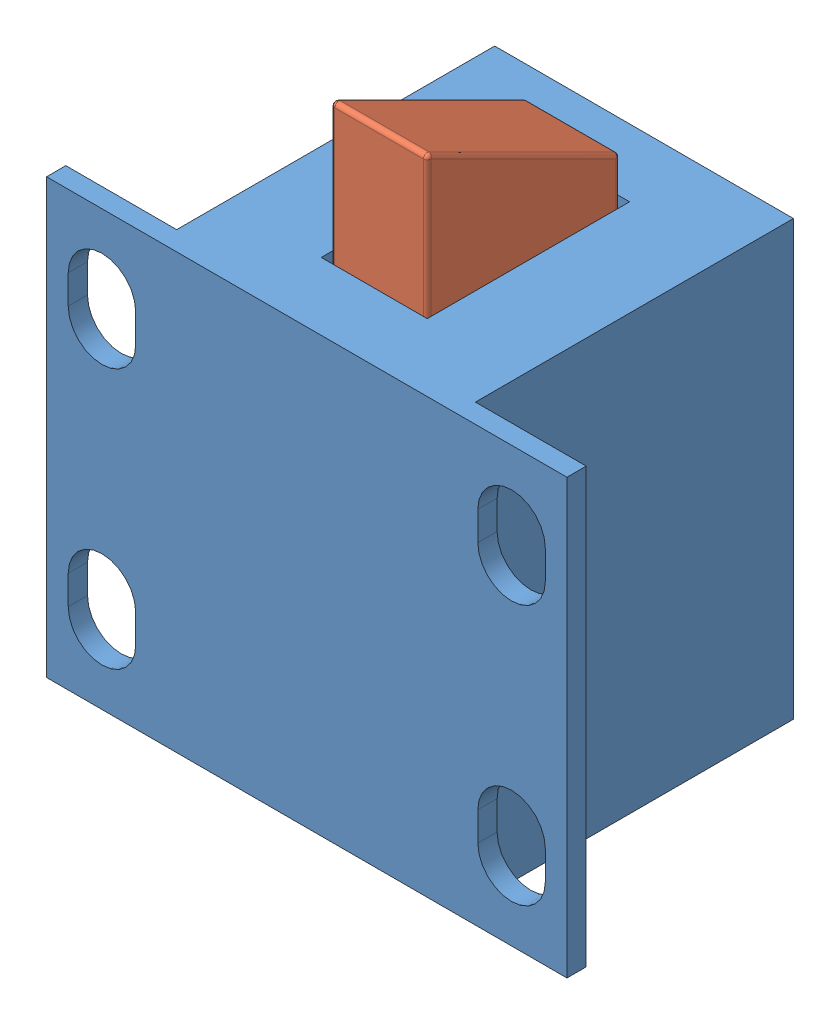
SolidWorks assembly solenoid_lock, configuration Default. Lengths in mm.
Overall size (27 29.52 17.5).
2 component instances, 2 part files, 3 mates.
Components (placement in the parent):
- body-1: body [Default] at (11.8618 3.6944 19.2033) size (27 22.5 17.5)
- lock-1: lock [Default] at (14.3618 23.3391 14.2033) x (0 0 1) z (0 -1 0) size (10 5 9.88)
Mates (geometry in assembly coordinates):
- Distance1: distance = 0.25 mm: plane of lock-1 through (9.3618 23.3391 24.2033) normal (0 0 1); plane of body-1 through (14.6118 16.1944 24.4533) normal (0 0 -1)
- Distance3: distance = 0.25 mm: plane of lock-1 through (14.3618 23.3391 14.2033) normal (1 0 0); plane of body-1 through (14.6118 16.1944 24.4533) normal (-1 0 0)
- LimitDistance1: limit distance = 7 mm: line of lock-1 through (9.5618 33.1944 23.9139) axis (1 0 0); plane of body-1 through (11.8618 26.1944 19.2033) normal (0 1 0)
